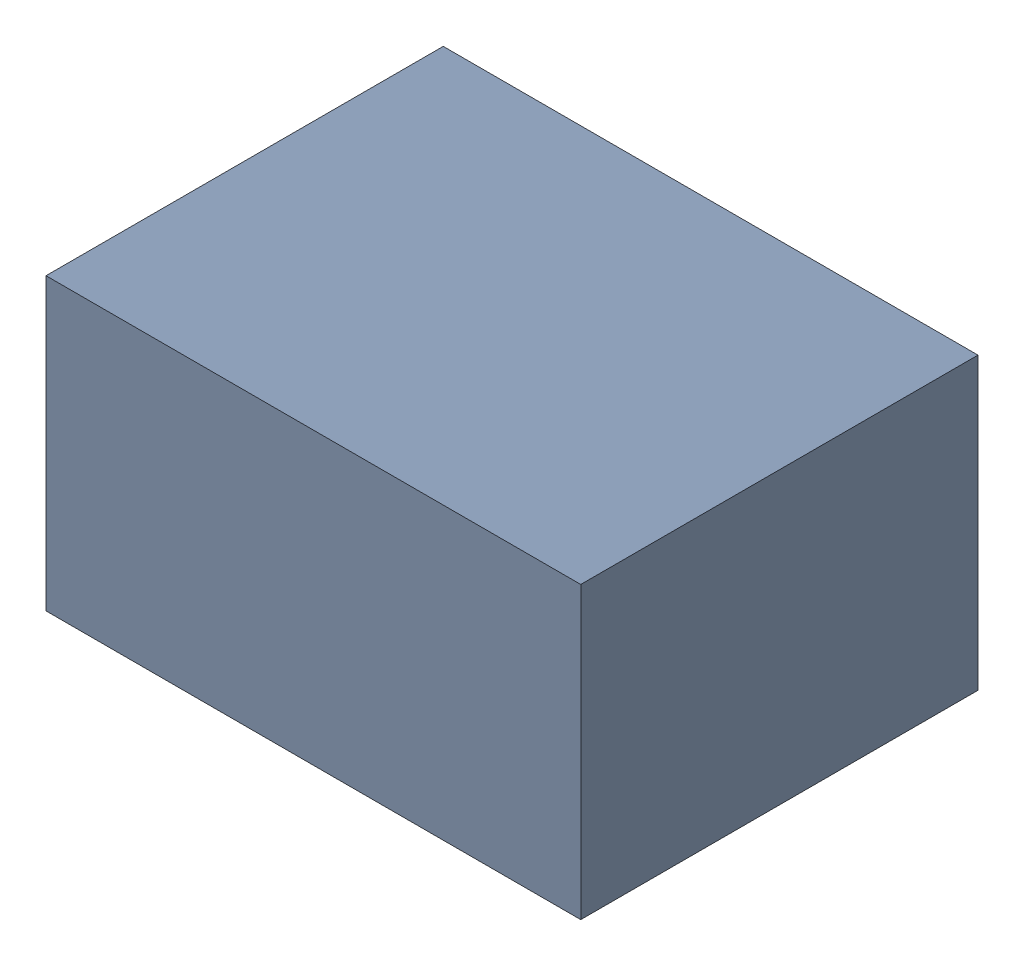
SolidWorks assembly C1_1, configuration Default. Lengths in mm.
Overall size (1.75 0.95 1.3).
2 component instances, 1 part files, 0 mates.
Components (placement in the parent):
- 5808184704-1: 5808184704 [Default] at (13.843 22.795 0) size (1.75 0.95 1.3)
  - Extruded_1_5-1: Extruded_1_5 [Default] at origin size (1.75 0.95 1.3)
